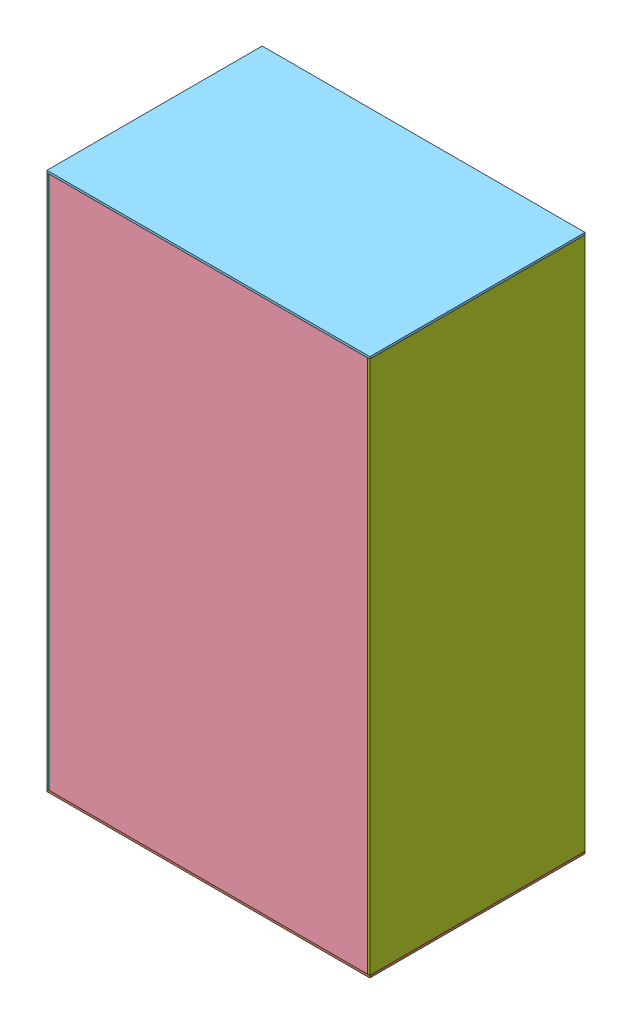
SolidWorks assembly SPR-V1 5000.01-A Electronics Enclosure, configuration Default. Lengths in mm.
Overall size (300 526.27 223.77).
30 component instances, 15 part files, 36 mates.
Components (placement in the parent):
- SPR-V1 5000.01-A Electronics Enclosure Front 496x296 2mm Sheet Steel-3: SPR-V1 5000.01-A Electronics Enclosure Front 496x296 2mm Sheet Steel [Default] at (284.7087 102.1521 237.9432) size (296 496 2)
- SPR-V1 5000.01-A Electronics Enclosure Bottom 300x200 2mm Sheet Steel-2: SPR-V1 5000.01-A Electronics Enclosure Bottom 300x200 2mm Sheet Steel [Default] at (284.7087 -147.8479 337.9432) x (1 0 0) z (0 1 0) size (300 200 2)
- SPR-V1 5000.02-A-A Electronics Enclosure Front Panel Mount Tab 6mm Sheet Steel M6-5: SPR-V1 5000.02-A-A Electronics Enclosure Front Panel Mount Tab 6mm Sheet Steel M6 [Default] at (136.7087 -145.8479 239.9432) x (1 0 0) z (0 -1 0) size (35.76 6 35.76)
- SPR-V1 5000.02-A-A Electronics Enclosure Front Panel Mount Tab 6mm Sheet Steel M6-6: SPR-V1 5000.02-A-A Electronics Enclosure Front Panel Mount Tab 6mm Sheet Steel M6 [Default] at (432.7087 -145.8479 245.9432) x (-1 0 0) z (0 -1 0) size (35.76 6 35.76)
- SPR-V1 5000.02-A-A Electronics Enclosure Front Panel Mount Tab 6mm Sheet Steel M6-7: SPR-V1 5000.02-A-A Electronics Enclosure Front Panel Mount Tab 6mm Sheet Steel M6 [Default] at (432.7087 350.1521 245.9432) x (0 -1 0) z (1 0 0) size (35.76 6 35.76)
- SPR-V1 5000.02-A-A Electronics Enclosure Front Panel Mount Tab 6mm Sheet Steel M6-8: SPR-V1 5000.02-A-A Electronics Enclosure Front Panel Mount Tab 6mm Sheet Steel M6 [Default] at (136.7087 350.1521 245.9432) x (1 0 0) z (0 1 0) size (35.76 6 35.76)
- SPR-V1 5000.01-A Electronics Enclosure Back 496x296 2mm Sheet Steel-4: SPR-V1 5000.01-A Electronics Enclosure Back 496x296 2mm Sheet Steel [Default] at (220.7454 71.4543 435.9432) size (296 496 2)
- SPR-V1 5000.01-A Electronics Enclosure Top 300x200 2mm Sheet Steel-3: SPR-V1 5000.01-A Electronics Enclosure Top 300x200 2mm Sheet Steel [Default] at (284.7087 352.1521 337.9432) x (1 0 0) z (0 -1 0) size (300 200 2)
- SPR-V1 5000.01-A Electronics Enclosure Right 496x200mm Sheet Steel-1: SPR-V1 5000.01-A Electronics Enclosure Right 496x200mm Sheet Steel [Default] at (136.7087 102.1521 337.9432) x (0 0 1) z (-1 0 0) size (200 496 2)
- SPR-V1 5000.01-A Electronics Enclosure Left 496x200mm Sheet Steel-1: SPR-V1 5000.01-A Electronics Enclosure Left 496x200mm Sheet Steel [Default] at (434.7087 102.1521 337.9432) x (0 0 1) z (-1 0 0) size (200 496 2)
- SPR-V1 5000.00-A REX C1000 PID Controler-1: SPR-V1 5000.00-A REX C1000 PID Controler [Default] at (382.6228 225.4392 230.0184) x (-1 0 0) z (0 0 -1) size (47.83 47.57 107.37)
- SPR-V1 5000.00-A REX C1000 PID Controler-2: SPR-V1 5000.00-A REX C1000 PID Controler [Default] at (382.6228 324.4392 230.0184) x (-1 0 0) z (0 0 -1) size (47.83 47.57 107.37)
- SPR-V1 5000.00-A Rotary Switch-1: SPR-V1 5000.00-A Rotary Switch [Default] at (241.5694 302.238 296.1693) x (-1 0 0) z (0 0 -1) size (48 48 55.77)
  - Iek ПКП - 10 0_1.stp-1: Iek ПКП - 10 0_1.stp [Default] at origin size (48 48 55.77)
    - Винт A2 ГОСТ 17473-80 M2.5-6gx10.stp-1: Винт A2 ГОСТ 17473-80 M2.5-6gx10.stp [Default] at (30.8608 -1.5859 79.2261) x (1 0 0) z (0 -1 0) size (4.5 11.67 4.5)
    - Iek ПКП - 10 0_1.stp-1: Iek ПКП - 10 0_1.stp [Default] at (30.8608 -1.5859 65.2261) x (-1 0 0) z (0 0 -1) size (26 38.02 16.92)
    - Корпус.stp-1: Корпус.stp [Default] at (30.8608 -1.5859 58.2261) size (48 48 40)
    - Винт A2 ГОСТ 17473-80 M3-6gx4.stp-1: Винт A2 ГОСТ 17473-80 M3-6gx4.stp [Default] at (18.8608 11.6141 45.2261) x (0.986395 0 0.164394) z (-0.164394 0 0.986395) size (5.5 6.06 5.5)
    - Винт A2 ГОСТ 17473-80 M3-6gx4.stp-2: Винт A2 ГОСТ 17473-80 M3-6gx4.stp [Default] at (18.8608 11.6141 31.2261) x (0.986395 0 0.164394) z (-0.164394 0 0.986395) size (5.5 6.06 5.5)
    - Винт A2 ГОСТ 17473-80 M3-6gx4.stp-3: Винт A2 ГОСТ 17473-80 M3-6gx4.stp [Default] at (42.8608 -14.7859 45.2261) x (-0.986395 0 0.164394) z (0.164394 0 0.986395) size (5.5 6.06 5.5)
    - Винт A2 ГОСТ 17473-80 M3-6gx4.stp-4: Винт A2 ГОСТ 17473-80 M3-6gx4.stp [Default] at (42.8608 -14.7859 31.2261) x (-0.986395 0 0.164394) z (0.164394 0 0.986395) size (5.5 6.06 5.5)
    - Винт A2 ГОСТ 17473-80 M3-6gx4.stp-5: Винт A2 ГОСТ 17473-80 M3-6gx4.stp [Default] at (42.8608 11.6141 31.2261) x (0.986395 0 -0.164394) z (0.164394 0 0.986395) size (5.5 6.06 5.5)
    - Винт A2 ГОСТ 17473-80 M3-6gx4.stp-6: Винт A2 ГОСТ 17473-80 M3-6gx4.stp [Default] at (42.8608 11.6141 45.2261) x (0.986395 0 -0.164394) z (0.164394 0 0.986395) size (5.5 6.06 5.5)
    - Винт A2 ГОСТ 17473-80 M3-6gx4.stp-7: Винт A2 ГОСТ 17473-80 M3-6gx4.stp [Default] at (18.8608 -14.7859 31.2261) x (-0.986395 0 -0.164394) z (-0.164394 0 0.986395) size (5.5 6.06 5.5)
    - Винт A2 ГОСТ 17473-80 M3-6gx4.stp-8: Винт A2 ГОСТ 17473-80 M3-6gx4.stp [Default] at (18.8608 -14.7859 45.2261) x (-0.986395 0 -0.164394) z (-0.164394 0 0.986395) size (5.5 6.06 5.5)
- SPR-V1 5000.00-A Emergency Stop-1: SPR-V1 5000.00-A Emergency Stop [Défaut] at (210.7087 201.6521 285.9432) x (1 0 0) z (0 0 -1) size (40 40 71)
- SPR-V1 14 M25 Cable Gland-1: SPR-V1 14 M25 Cable Gland [M20] at (374.7051 -130.473 337.9415) x (0.546944 0 -0.837169) z (-0.837169 0 -0.546944) size (33.12 53.02 29.38)
- SPR-V1 14 M25 Cable Gland-2: SPR-V1 14 M25 Cable Gland [M20] at (314.7051 -130.473 337.9415) x (0.546944 0 -0.837169) z (-0.837169 0 -0.546944) size (33.12 53.02 29.38)
- SPR-V1 14 M25 Cable Gland-3: SPR-V1 14 M25 Cable Gland [M20] at (254.7051 -130.473 337.9415) x (0.546944 0 -0.837169) z (-0.837169 0 -0.546944) size (33.12 53.02 29.38)
- SPR-V1 16 M10 Gland-1: SPR-V1 16 M10 Gland [M20] at (194.712 -129.6801 337.9361) x (-0.837169 0 -0.546944) z (-0.546944 0 0.837169) size (13.25 53.02 11.75)
Mates (geometry in assembly coordinates):
- Coincident4: coincident: plane of SPR-V1 5000.01-A Electronics Enclosure Front 496x296 2mm Sheet Steel-3 through (432.7087 -145.8479 239.9432) normal (0 -1 0); plane of SPR-V1 5000.01-A Electronics Enclosure Bottom 300x200 2mm Sheet Steel-2 through (284.7087 -145.8479 337.9432) normal (0 1 0)
- Coincident5: coincident: plane of SPR-V1 5000.01-A Electronics Enclosure Front 496x296 2mm Sheet Steel-3 through (284.7087 102.1521 237.9432) normal (0 0 -1); plane of SPR-V1 5000.01-A Electronics Enclosure Bottom 300x200 2mm Sheet Steel-2 through (434.7087 -145.8479 237.9432) normal (0 0 -1)
- Coincident24: coincident: plane of SPR-V1 5000.01-A Electronics Enclosure Bottom 300x200 2mm Sheet Steel-2 through (284.7087 -145.8479 337.9432) normal (0 1 0); plane of SPR-V1 5000.02-A-A Electronics Enclosure Front Panel Mount Tab 6mm Sheet Steel M6-5 through (139.7087 -145.8479 245.9432) normal (0 -1 0)
- Coincident27: coincident: plane of SPR-V1 5000.01-A Electronics Enclosure Bottom 300x200 2mm Sheet Steel-2 through (284.7087 -145.8479 337.9432) normal (0 1 0); plane of SPR-V1 5000.02-A-A Electronics Enclosure Front Panel Mount Tab 6mm Sheet Steel M6-6 through (429.7087 -145.8479 239.9432) normal (0 -1 0)
- Coincident32: coincident: plane of SPR-V1 5000.01-A Electronics Enclosure Front 496x296 2mm Sheet Steel-3 through (284.7087 102.1521 239.9432) normal (0 0 1); plane of SPR-V1 5000.02-A-A Electronics Enclosure Front Panel Mount Tab 6mm Sheet Steel M6-5 through (139.7087 -142.8479 239.9432) normal (0 0 -1)
- Coincident33: coincident: plane of SPR-V1 5000.01-A Electronics Enclosure Front 496x296 2mm Sheet Steel-3 through (284.7087 102.1521 239.9432) normal (0 0 1); plane of SPR-V1 5000.02-A-A Electronics Enclosure Front Panel Mount Tab 6mm Sheet Steel M6-6 through (429.7087 -142.8479 239.9432) normal (0 0 -1)
- Coincident34: coincident: plane of SPR-V1 5000.01-A Electronics Enclosure Front 496x296 2mm Sheet Steel-3 through (284.7087 102.1521 239.9432) normal (0 0 1); plane of SPR-V1 5000.02-A-A Electronics Enclosure Front Panel Mount Tab 6mm Sheet Steel M6-7 through (429.7087 347.1521 239.9432) normal (0 0 -1)
- Coincident35: coincident: plane of SPR-V1 5000.01-A Electronics Enclosure Front 496x296 2mm Sheet Steel-3 through (284.7087 102.1521 239.9432) normal (0 0 1); plane of SPR-V1 5000.02-A-A Electronics Enclosure Front Panel Mount Tab 6mm Sheet Steel M6-8 through (139.7087 347.1521 239.9432) normal (0 0 -1)
- Coincident38: coincident: plane of SPR-V1 5000.01-A Electronics Enclosure Bottom 300x200 2mm Sheet Steel-2 through (284.7087 -145.8479 337.9432) normal (0 1 0); plane of SPR-V1 5000.01-A Electronics Enclosure Back 496x296 2mm Sheet Steel-4 through (432.7087 -145.8479 437.9432) normal (0 -1 0)
- Coincident41: coincident: plane of SPR-V1 5000.01-A Electronics Enclosure Back 496x296 2mm Sheet Steel-4 through (220.7454 71.4543 437.9432) normal (0 0 1); plane of SPR-V1 5000.01-A Electronics Enclosure Top 300x200 2mm Sheet Steel-3 through (434.7087 350.1521 437.9432) normal (0 0 1)
- Coincident42: coincident: plane of SPR-V1 5000.01-A Electronics Enclosure Top 300x200 2mm Sheet Steel-3 through (284.7087 350.1521 337.9432) normal (0 -1 0); plane of SPR-V1 5000.01-A Electronics Enclosure Right 496x200mm Sheet Steel-1 through (134.7087 350.1521 437.9432) normal (0 1 0)
- Coincident43: coincident: plane of SPR-V1 5000.01-A Electronics Enclosure Front 496x296 2mm Sheet Steel-3 through (136.7087 350.1521 239.9432) normal (-1 0 0); plane of SPR-V1 5000.01-A Electronics Enclosure Right 496x200mm Sheet Steel-1 through (136.7087 102.1521 337.9432) normal (1 0 0)
- Coincident44: coincident: plane of SPR-V1 5000.01-A Electronics Enclosure Top 300x200 2mm Sheet Steel-3 through (434.7087 350.1521 437.9432) normal (0 0 1); plane of SPR-V1 5000.01-A Electronics Enclosure Right 496x200mm Sheet Steel-1 through (134.7087 350.1521 437.9432) normal (0 0 1)
- Coincident45: coincident: plane of SPR-V1 5000.01-A Electronics Enclosure Front 496x296 2mm Sheet Steel-3 through (284.7087 102.1521 237.9432) normal (0 0 -1); plane of SPR-V1 5000.01-A Electronics Enclosure Right 496x200mm Sheet Steel-1 through (134.7087 350.1521 237.9432) normal (0 0 -1)
- Coincident47: coincident: plane of SPR-V1 5000.01-A Electronics Enclosure Back 496x296 2mm Sheet Steel-4 through (220.7454 71.4543 437.9432) normal (0 0 1); plane of SPR-V1 5000.01-A Electronics Enclosure Left 496x200mm Sheet Steel-1 through (432.7087 350.1521 437.9432) normal (0 0 1)
- Coincident48: coincident: plane of SPR-V1 5000.01-A Electronics Enclosure Top 300x200 2mm Sheet Steel-3 through (284.7087 350.1521 337.9432) normal (0 -1 0); plane of SPR-V1 5000.01-A Electronics Enclosure Left 496x200mm Sheet Steel-1 through (432.7087 350.1521 437.9432) normal (0 1 0)
- Width1: width: plane of SPR-V1 5000.01-A Electronics Enclosure Front 496x296 2mm Sheet Steel-3 through (381.4587 323.4021 239.9432) normal (-1 0 0); plane of SPR-V1 5000.01-A Electronics Enclosure Front 496x296 2mm Sheet Steel-3 through (335.9587 323.4021 239.9432) normal (1 0 0); plane of SPR-V1 5000.00-A REX C1000 PID Controler-2 through (334.7946 276.865 230.0184) normal (-1 0 0); plane of SPR-V1 5000.00-A REX C1000 PID Controler-2 through (382.6228 324.4392 230.0184) normal (1 0 0)
- Width2: width: plane of SPR-V1 5000.01-A Electronics Enclosure Front 496x296 2mm Sheet Steel-3 through (335.9587 323.4021 239.9432) normal (0 -1 0); plane of SPR-V1 5000.01-A Electronics Enclosure Front 496x296 2mm Sheet Steel-3 through (335.9587 277.9021 239.9432) normal (0 1 0); plane of SPR-V1 5000.00-A REX C1000 PID Controler-2 through (334.7946 324.4392 230.0184) normal (0 1 0); plane of SPR-V1 5000.00-A REX C1000 PID Controler-2 through (382.6228 276.865 230.0184) normal (0 -1 0)
- Coincident51: coincident: plane of SPR-V1 5000.01-A Electronics Enclosure Front 496x296 2mm Sheet Steel-3 through (284.7087 102.1521 237.9432) normal (0 0 -1); plane of SPR-V1 5000.00-A REX C1000 PID Controler-2 through (358.7087 300.6521 237.9432) normal (0 0 1)
- Width3: width: plane of SPR-V1 5000.00-A REX C1000 PID Controler-1 through (334.7946 177.865 230.0184) normal (-1 0 0); plane of SPR-V1 5000.00-A REX C1000 PID Controler-1 through (382.6228 225.4392 230.0184) normal (1 0 0); plane of SPR-V1 5000.01-A Electronics Enclosure Front 496x296 2mm Sheet Steel-3 through (381.4587 178.9021 239.9432) normal (-1 0 0); plane of SPR-V1 5000.01-A Electronics Enclosure Front 496x296 2mm Sheet Steel-3 through (335.9587 178.9021 239.9432) normal (1 0 0)
- Width4: width: plane of SPR-V1 5000.00-A REX C1000 PID Controler-1 through (334.7946 225.4392 230.0184) normal (0 1 0); plane of SPR-V1 5000.00-A REX C1000 PID Controler-1 through (382.6228 177.865 230.0184) normal (0 -1 0); plane of SPR-V1 5000.01-A Electronics Enclosure Front 496x296 2mm Sheet Steel-3 through (335.9587 224.4021 239.9432) normal (0 -1 0); plane of SPR-V1 5000.01-A Electronics Enclosure Front 496x296 2mm Sheet Steel-3 through (335.9587 178.9021 239.9432) normal (0 1 0)
- Coincident52: coincident: plane of SPR-V1 5000.01-A Electronics Enclosure Front 496x296 2mm Sheet Steel-3 through (284.7087 102.1521 237.9432) normal (0 0 -1); plane of SPR-V1 5000.00-A REX C1000 PID Controler-1 through (358.7087 201.6521 237.9432) normal (0 0 1)
- Coincident53: coincident: plane of SPR-V1 5000.01-A Electronics Enclosure Front 496x296 2mm Sheet Steel-3 through (284.7087 102.1521 237.9432) normal (0 0 -1); plane of SPR-V1 5000.00-A Rotary Switch-1/Iek ПКП - 10 0_1.stp-1/Корпус.stp-1 through (210.7087 300.6521 237.9432) normal (0 0 1)
- Concentric1: concentric: cylinder of SPR-V1 5000.01-A Electronics Enclosure Front 496x296 2mm Sheet Steel-3 through (210.7087 300.6521 239.9432) axis (0 0 -1) radius 22; cylinder of SPR-V1 5000.00-A Rotary Switch-1/Iek ПКП - 10 0_1.stp-1/Корпус.stp-1 through (210.7087 300.6521 237.9432) axis (0 0 1) radius 18
- Parallel3: parallel: plane of SPR-V1 5000.01-A Electronics Enclosure Top 300x200 2mm Sheet Steel-3 through (284.7087 352.1521 337.9432) normal (0 1 0); plane of SPR-V1 5000.00-A Rotary Switch-1/Iek ПКП - 10 0_1.stp-1/Корпус.stp-1 through (234.7087 324.6521 237.9432) normal (0 1 0)
- Concentric2: concentric: cylinder of SPR-V1 5000.01-A Electronics Enclosure Front 496x296 2mm Sheet Steel-3 through (210.7087 201.6521 239.9432) axis (0 0 -1) radius 11; cylinder of SPR-V1 5000.00-A Emergency Stop-1 through (210.7087 201.6521 236.4432) axis (0 0 1) radius 11
- Coincident56: coincident: plane of SPR-V1 5000.01-A Electronics Enclosure Front 496x296 2mm Sheet Steel-3 through (284.7087 102.1521 237.9432) normal (0 0 -1); plane of SPR-V1 5000.00-A Emergency Stop-1 through (210.7087 190.6521 237.9432) normal (0 0 1)
- Parallel4: parallel: plane of SPR-V1 5000.01-A Electronics Enclosure Left 496x200mm Sheet Steel-1 through (432.7087 102.1521 337.9432) normal (-1 0 0); plane of SPR-V1 5000.00-A Emergency Stop-1 through (195.7087 201.6521 285.9432) normal (-1 0 0)
- Concentric3: concentric: cylinder of SPR-V1 5000.01-A Electronics Enclosure Bottom 300x200 2mm Sheet Steel-2 through (374.7087 -145.8479 337.9432) axis (0 -1 0) radius 13; cylinder of SPR-V1 14 M25 Cable Gland-1 through (374.7087 -125.7989 337.9432) axis (0 1 0) radius 14.6875
- Coincident57: coincident: plane of SPR-V1 5000.01-A Electronics Enclosure Bottom 300x200 2mm Sheet Steel-2 through (284.7087 -147.8479 337.9432) normal (0 -1 0); plane of SPR-V1 14 M25 Cable Gland-1 through (366.6754 -147.8479 350.2391) normal (0 1 0)
- Concentric4: concentric: cylinder of SPR-V1 5000.01-A Electronics Enclosure Bottom 300x200 2mm Sheet Steel-2 through (314.7087 -145.8479 337.9432) axis (0 -1 0) radius 13; cylinder of SPR-V1 14 M25 Cable Gland-2 through (314.7087 -125.7989 337.9432) axis (0 1 0) radius 14.6875
- Coincident58: coincident: plane of SPR-V1 5000.01-A Electronics Enclosure Bottom 300x200 2mm Sheet Steel-2 through (284.7087 -147.8479 337.9432) normal (0 -1 0); plane of SPR-V1 14 M25 Cable Gland-2 through (306.6754 -147.8479 350.2391) normal (0 1 0)
- Concentric5: concentric: cylinder of SPR-V1 5000.01-A Electronics Enclosure Bottom 300x200 2mm Sheet Steel-2 through (254.7087 -145.8479 337.9432) axis (0 -1 0) radius 13; cylinder of SPR-V1 14 M25 Cable Gland-3 through (254.7087 -125.7989 337.9432) axis (0 1 0) radius 14.6875
- Coincident59: coincident: plane of SPR-V1 5000.01-A Electronics Enclosure Bottom 300x200 2mm Sheet Steel-2 through (284.7087 -147.8479 337.9432) normal (0 -1 0); plane of SPR-V1 14 M25 Cable Gland-3 through (246.6754 -147.8479 350.2391) normal (0 1 0)
- Concentric7: concentric: cylinder of SPR-V1 5000.01-A Electronics Enclosure Bottom 300x200 2mm Sheet Steel-2 through (194.7087 -145.8479 337.9432) axis (0 -1 0) radius 5.5; cylinder of SPR-V1 16 M10 Gland-1 through (194.7087 -144.6783 337.9432) axis (0 1 0) radius 5
- Coincident63: coincident: plane of SPR-V1 5000.01-A Electronics Enclosure Bottom 300x200 2mm Sheet Steel-2 through (284.7087 -147.8479 337.9432) normal (0 -1 0); plane of SPR-V1 16 M10 Gland-1 through (199.627 -147.8479 341.1565) normal (0 1 0)
